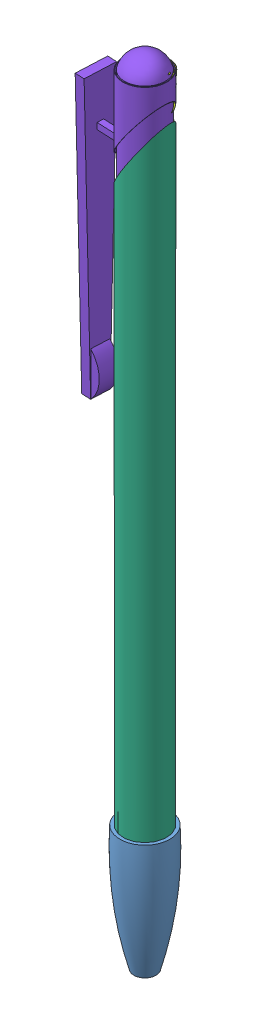
SolidWorks assembly PEN ASSEMBLY, configuration Default. Lengths in mm.
Overall size (13.22 127.46 8.15).
8 component instances, 8 part files, 7 mates.
Components (placement in the parent):
- PEN TIP-2: PEN TIP [Default] at (11.1752 24.7878 20.5704) x (0 0 1) z (1 0 0) size (8.15 26.18 8.15)
- SPRING (TIP)-1: SPRING (TIP) [Default] at (11.4342 17.9118 20.5294) size (4.1 32.28 4.73)
- INK CHAMBER, BALLPOINT TIP-1: INK CHAMBER, BALLPOINT TIP [Default] at (11.1752 7.9609 20.5704) x (0.996676 0 -0.081465) z (0.081465 0 0.996676) size (3.56 97.99 3.56)
- THRUST DEVICE-1: THRUST DEVICE [Default] at (11.1752 93.9458 20.5704) x (0.973968 0 0.226686) z (-0.226686 0 0.973968) size (5 10.01 5)
- CAM-1: CAM [Default] at (11.1752 105.4724 20.5704) x (0.999971 0 -0.007631) z (0.007631 0 0.999971) size (5 10.17 5)
- PEN BODY-1: PEN BODY [Default] at (11.1752 18.6506 20.5704) x (0.996335 0 -0.085532) z (0.085532 0 0.996335) size (7.01 99.03 7.01)
- SPRING (CAP)-1: SPRING (CAP) [Default] at (11.6637 97.4612 20.4321) x (0.999985 -0.004883 -0.002333) z (0.00251 0.036481 0.999331) size (4.83 26.88 5.58)
- PEN CAP-1: PEN CAP [Default] at (11.1752 93.7034 20.5704) x (0.045483 0 -0.998965) z (0 -1 0) size (7.01 12.5 51.54)
Mates (geometry in assembly coordinates):
- Concentric1: concentric anti-aligned: cylinder of PEN TIP-2 through (11.1752 24.7878 20.5704) axis (0 -1 0) radius 1.7145; circle of INK CHAMBER, BALLPOINT TIP-1
- Tangent1: tangent aligned: face of PEN TIP-2; cylinder of INK CHAMBER, BALLPOINT TIP-1 through (11.1752 97.9531 20.5704) axis (0 -1 0) radius 1.778
- Concentric2: concentric aligned: circle of INK CHAMBER, BALLPOINT TIP-1; circle of THRUST DEVICE-1
- Concentric3: concentric aligned: circle of THRUST DEVICE-1; circle of CAM-1
- Concentric4: concentric anti-aligned: circle of PEN TIP-2; circle of PEN BODY-1
- Tangent5: tangent: circle of assembly; face of SPRING (CAP)-1; circle of PEN CAP-1
- Concentric5: concentric anti-aligned: circle of PEN BODY-1; circle of PEN CAP-1
